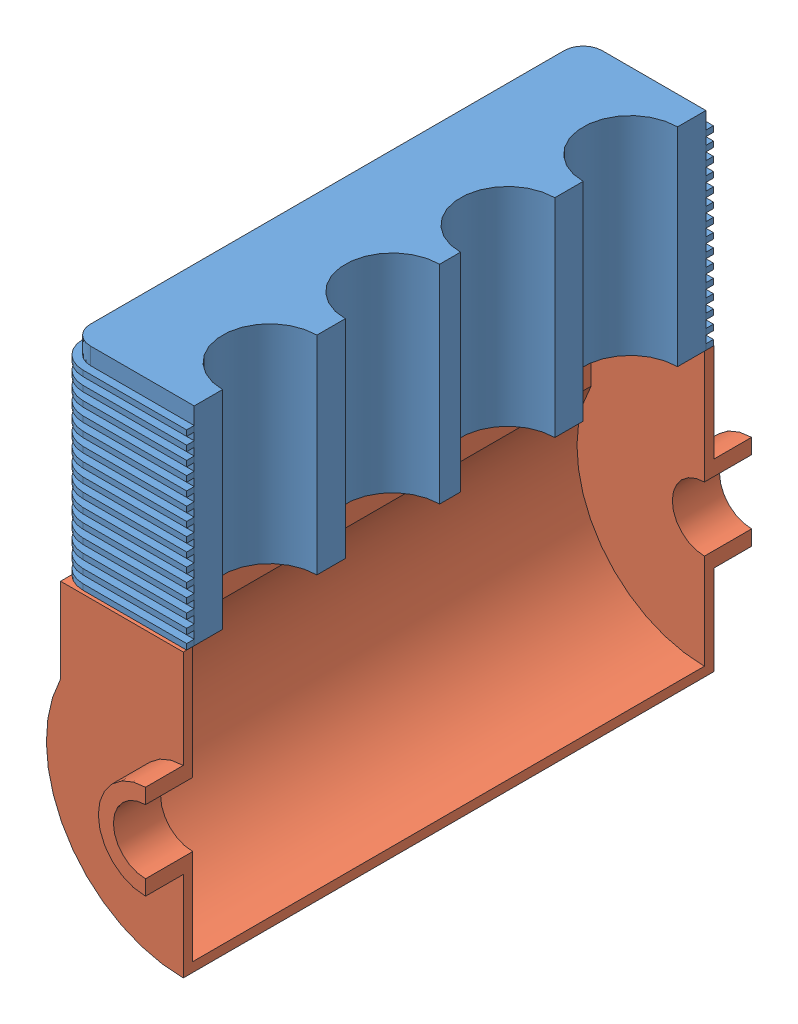
SolidWorks assembly Assem1, configuration Default. Lengths in mm.
Overall size (1841.5 6591.3 8153.4).
2 component instances, 2 part files, 6 mates.
Components (placement in the parent):
- upper block-1: upper block [Default] at (-2078.8003 6512.4222 6232.6792) x (0 0 1) z (1 0 0) size (7086.6 2794 1752.6)
- lower block-1: lower block [Default] at (-2078.8003 1762.6222 13263.1091) size (1841.5 3797.3 8153.4)
Mates (geometry in assembly coordinates):
- Coincident7: coincident: plane of upper block-1 through (-2078.8003 3718.4222 12817.4461) normal (1 0 0); plane of lower block-1 through (-2078.8003 2397.6222 13136.1091) normal (1 0 0)
- Coincident9: coincident: plane of upper block-1 through (-2078.8003 3718.4222 12817.4461) normal (1 0 0); plane of lower block-1 through (-2078.8003 2397.6222 13136.1091) normal (1 0 0)
- Coincident11: coincident: plane of upper block-1 through (-2078.8003 3718.4222 12735.0792) normal (1 0 0); plane of lower block-1 through (-2078.8003 2397.6222 13136.1091) normal (1 0 0)
- Coincident12: coincident: plane of upper block-1 through (-2078.8003 3718.4222 12735.0792) normal (1 0 0); plane of lower block-1 through (-2078.8003 2397.6222 13136.1091) normal (1 0 0)
- Coincident13: coincident: plane of upper block-1 through (-2078.8003 3718.4222 6232.6792) normal (1 0 0); plane of lower block-1 through (-2078.8003 2397.6222 6252.7091) normal (1 0 0)
- Coincident14: coincident anti-aligned: plane of upper block-1 through (-3475.8003 3718.4222 6486.6792) normal (0 -1 0); plane of lower block-1 through (-2078.8003 3718.4222 13136.1091) normal (0 1 0)
